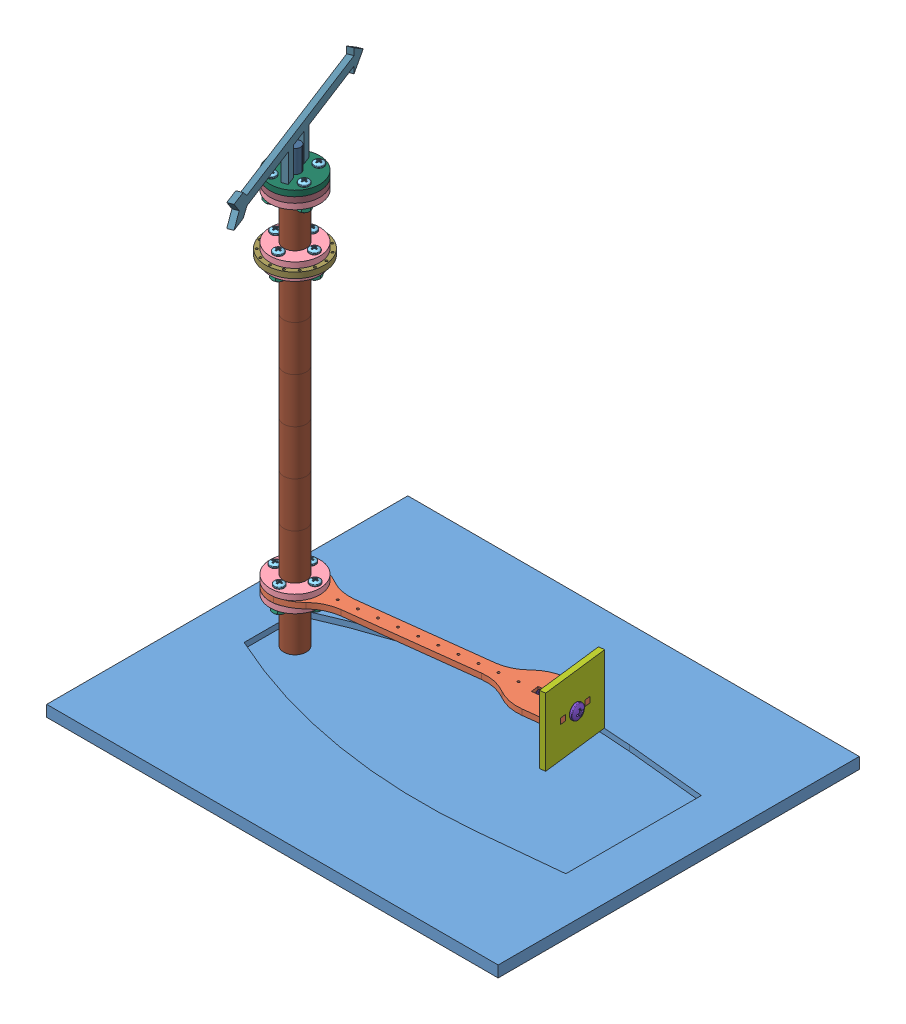
SolidWorks assembly boat_Assem1, configuration Default. Lengths in mm.
Overall size (254 259.72 203.2).
51 component instances, 15 part files, 81 mates.
Components (placement in the parent):
- base-1: base [Default] at (17.7481 -11.9296 -1.2606) size (254 6.35 203.2)
- boom_assembly-1: boom_assembly [Default] at (-15.1663 24.5072 -8.1814) x (0.992691 0 -0.12068) z (0.12068 0 0.992691) size (156.63 14.77 30.54)
  - boom-1: boom [Default] at (5.8183 -4.6868 0.1139) size (155.58 3.17 27.94)
  - bearing_57155K356-1: bearing_57155K356 [57155K356] at (-56.4117 -3.0993 0.1139) x (1 0 0) z (0 1 0) size (12.7 12.7 3.17)
  - boom_bearing_cap_hex-1: boom_bearing_cap_hex [Default] at (-56.4117 1.6632 0.1139) x (-1 0 0) z (0 0 1) size (27.94 3.17 27.94)
  - boom_bearing_cap_hex-3: boom_bearing_cap_hex [Default] at (-56.4117 -4.6868 0.1139) x (-1 0 0) z (0 0 1) size (27.94 3.17 27.94)
  - 440_1-2_90272A110-1: 440_1-2_90272A110 [90272A110] at (-46.2517 -11.0368 0.1139) x (1 0 0) z (0 1 0) size (5.56 5.56 14.77)
  - 440_1-2_90272A110-2: 440_1-2_90272A110 [90272A110] at (-56.4117 -11.0368 10.2739) x (1 0 0) z (0 1 0) size (5.56 5.56 14.77)
  - 440_1-2_90272A110-3: 440_1-2_90272A110 [90272A110] at (-66.5717 -11.0368 0.1139) x (1 0 0) z (0 1 0) size (5.56 5.56 14.77)
  - 440_1-2_90272A110-4: 440_1-2_90272A110 [90272A110] at (-56.4117 -11.0368 -10.0461) x (1 0 0) z (0 1 0) size (5.56 5.56 14.77)
  - 440_nut_90480A005-9: 440_nut_90480A005 [90480A005] at (-66.5717 -7.8618 0.1139) x (-0.837169 0 -0.546944) z (-0.546944 0 0.837169) size (6.35 2.38 8.06)
  - 440_nut_90480A005-10: 440_nut_90480A005 [90480A005] at (-56.4117 -7.8618 -10.0461) x (-0.837169 0 -0.546944) z (-0.546944 0 0.837169) size (6.35 2.38 8.06)
  - 440_nut_90480A005-11: 440_nut_90480A005 [90480A005] at (-46.2517 -7.8618 0.1139) x (-0.837169 0 -0.546944) z (-0.546944 0 0.837169) size (6.35 2.38 8.06)
  - 440_nut_90480A005-12: 440_nut_90480A005 [90480A005] at (-56.4117 -7.8618 10.2739) x (-0.837169 0 -0.546944) z (-0.546944 0 0.837169) size (6.35 2.38 8.06)
- calibration_part-1: calibration_part [Default] at (69.4182 21.4079 -18.3496) x (0.12068 0 0.992691) z (-0.992691 0 0.12068) size (38.1 38.1 3.17)
- 832screw_75-1: 832screw_75 [90272A197] at (50.5074 21.4079 -16.0506) x (0.015603 0.991607 0.128345) z (0.992691 0 -0.12068) size (8.18 8.18 22.03)
- 832squareNut-1: 832squareNut [94855A119] at (58.0717 21.4079 -16.9702) x (0 -1 0) z (0.12068 0 0.992691) size (8.73 3.17 8.73)
- mast-1: mast [Default] at (-71.1519 -11.9296 -1.2606) x (-0.874096 0 0.485753) z (-0.485753 0 -0.874096) size (6.35 247.65 6.35)
- spacer_93717A436-1: spacer_93717A436 [93717A436] at (-71.1519 3.9454 -1.2606) x (1 0 0) z (0 -1 0) size (12.7 12.7 25.4)
- sail_top-1: sail_top [Default] at (-71.1519 181.7454 -1.2606) x (-0.997292 0 0.073545) z (-0.073545 0 -0.997292) size (33.02 3.17 33.02)
- boom_bearing_cap_hex-1: boom_bearing_cap_hex [Default] at (-71.1519 178.5704 -1.2606) x (-0.997292 0 0.073545) z (-0.073545 0 -0.997292) size (27.94 3.17 27.94)
- boom_bearing_cap_hex-2: boom_bearing_cap_hex [Default] at (-71.1519 188.0954 -1.2606) x (-0.997292 0 0.073545) z (0.073545 0 0.997292) size (27.94 3.17 27.94)
- bearing_57155K356-1: bearing_57155K356 [57155K356] at (-71.1519 183.3329 -1.2606) x (1 0 0) z (0 -1 0) size (12.7 12.7 3.17)
- 440_1-2_90272A110-1: 440_1-2_90272A110 [90272A110] at (-71.8991 175.3954 -11.3931) x (1 0 0) z (0 1 0) size (5.56 5.56 14.77)
- 440_1-2_90272A110-2: 440_1-2_90272A110 [90272A110] at (-81.2844 175.3954 -0.5134) x (1 0 0) z (0 1 0) size (5.56 5.56 14.77)
- 440_1-2_90272A110-3: 440_1-2_90272A110 [90272A110] at (-61.0194 175.3954 -2.0078) x (1 0 0) z (0 1 0) size (5.56 5.56 14.77)
- 440_1-2_90272A110-4: 440_1-2_90272A110 [90272A110] at (-70.4047 175.3954 8.8719) x (1 0 0) z (0 1 0) size (5.56 5.56 14.77)
- 440_nut_90480A005-1: 440_nut_90480A005 [90480A005] at (-81.2844 178.5704 -0.5134) x (-0.837169 0 -0.546944) z (-0.546944 0 0.837169) size (6.35 2.38 8.06)
- 440_nut_90480A005-2: 440_nut_90480A005 [90480A005] at (-70.4047 178.5704 8.8719) x (-0.837169 0 -0.546944) z (-0.546944 0 0.837169) size (6.35 2.38 8.06)
- 440_nut_90480A005-3: 440_nut_90480A005 [90480A005] at (-61.0194 178.5704 -2.0078) x (-0.837169 0 -0.546944) z (-0.546944 0 0.837169) size (6.35 2.38 8.06)
- 440_nut_90480A005-4: 440_nut_90480A005 [90480A005] at (-71.8991 178.5704 -11.3931) x (-0.837169 0 -0.546944) z (-0.546944 0 0.837169) size (6.35 2.38 8.06)
- spacer_93717A436-2: spacer_93717A436 [93717A436] at (-71.1519 64.2704 -1.2606) x (1 0 0) z (0 -1 0) size (12.7 12.7 25.4)
- spacer_93717A436-4: spacer_93717A436 [93717A436] at (-71.1519 89.6704 -1.2606) x (1 0 0) z (0 -1 0) size (12.7 12.7 25.4)
- spacer_93717A436-6: spacer_93717A436 [93717A436] at (-71.1519 38.8704 -1.2606) x (0.837169 0 0.546944) z (0 1 0) size (12.7 12.7 25.4)
- spacer_93717A436-7: spacer_93717A436 [93717A436] at (-71.1519 115.0704 -1.2606) x (1 0 0) z (0 -1 0) size (12.7 12.7 25.4)
- spacer_93717A436-8: spacer_93717A436 [93717A436] at (-71.1519 140.4704 -1.2606) x (1 0 0) z (0 -1 0) size (12.7 12.7 25.4)
- spacer_93717A436-9: spacer_93717A436 [93717A436] at (-71.1519 165.8704 -1.2606) x (1 0 0) z (0 -1 0) size (12.7 12.7 25.4)
- spacer_93717A436-10: spacer_93717A436 [93717A436] at (-71.1519 200.7954 -1.2606) x (1 0 0) z (0 -1 0) size (12.7 12.7 25.4)
- vane_attach-1: vane_attach [Default] at (-71.1519 219.8454 -1.2606) x (0.914446 0 0.404708) z (0.404708 0 -0.914446) size (27.94 3.17 27.94)
- boom_bearing_cap_hex-4: boom_bearing_cap_hex [Default] at (-71.1519 213.4954 -1.2606) x (-0.404708 0 0.914446) z (-0.914446 0 -0.404708) size (27.94 3.17 27.94)
- bearing_57155K356-2: bearing_57155K356 [57155K356] at (-71.1519 218.2579 -1.2606) x (1 0 0) z (0 -1 0) size (12.7 12.7 3.17)
- wind_vane-1: wind_vane [Default] at (-69.6711 241.4354 -1.8328) x (0.360439 0 0.932783) z (-0.932783 0 0.360439) size (127 27.94 3.17)
- boom_bearing_cap-1: boom_bearing_cap [Default] at (-71.1519 223.0204 -1.2606) x (0.914446 0 0.404708) z (0.404708 0 -0.914446) size (27.94 3.17 27.94)
- 440_1-2_90272A110-5: 440_1-2_90272A110 [90272A110] at (-75.2638 210.3204 8.0301) x (1 0 0) z (0 1 0) size (5.56 5.56 14.77)
- 440_1-2_90272A110-6: 440_1-2_90272A110 [90272A110] at (-67.0401 210.3204 -10.5514) x (1 0 0) z (0 1 0) size (5.56 5.56 14.77)
- 440_1-2_90272A110-7: 440_1-2_90272A110 [90272A110] at (-80.4427 210.3204 -5.3725) x (1 0 0) z (0 1 0) size (5.56 5.56 14.77)
- 440_1-2_90272A110-8: 440_1-2_90272A110 [90272A110] at (-61.8611 210.3204 2.8512) x (1 0 0) z (0 1 0) size (5.56 5.56 14.77)
- 440_nut_90480A005-5: 440_nut_90480A005 [90480A005] at (-61.8611 213.4954 2.8512) x (-0.837169 0 -0.546944) z (-0.546944 0 0.837169) size (6.35 2.38 8.06)
- 440_nut_90480A005-6: 440_nut_90480A005 [90480A005] at (-67.0401 213.4954 -10.5514) x (-0.837169 0 -0.546944) z (-0.546944 0 0.837169) size (6.35 2.38 8.06)
- 440_nut_90480A005-7: 440_nut_90480A005 [90480A005] at (-75.2638 213.4954 8.0301) x (-0.837169 0 -0.546944) z (-0.546944 0 0.837169) size (6.35 2.38 8.06)
- 440_nut_90480A005-8: 440_nut_90480A005 [90480A005] at (-80.4427 213.4954 -5.3725) x (-0.837169 0 -0.546944) z (-0.546944 0 0.837169) size (6.35 2.38 8.06)
Mates (geometry in assembly coordinates):
- Coincident5: coincident anti-aligned: plane of boom_assembly-1/boom-1 through (64.5805 22.9954 -31.8343) normal (0.992691 0 -0.12068); plane of calibration_part-1 through (66.2664 21.4079 -17.9664) normal (-0.992691 0 0.12068)
- Coincident6: coincident anti-aligned: plane of boom_assembly-1/boom-1 through (70.1845 22.9954 -12.046) normal (-0.12068 0 -0.992691); plane of calibration_part-1 through (70.1845 22.9954 -12.046) normal (0.12068 0 0.992691)
- Coincident7: coincident anti-aligned: plane of boom_assembly-1/boom-1 through (-9.3767 22.9954 -8.7706) normal (0 1 0); plane of calibration_part-1 through (70.1845 22.9954 -12.046) normal (0 -1 0)
- Coincident8: coincident anti-aligned: plane of calibration_part-1 through (69.4182 21.4079 -18.3496) normal (0.992691 0 -0.12068); plane of 832screw_75-1 through (69.4182 21.4079 -18.3496) normal (-0.992691 0 0.12068)
- Concentric3: concentric anti-aligned: circle of calibration_part-1; circle of 832screw_75-1
- Coincident9: coincident anti-aligned: plane of boom_assembly-1/boom-1 through (60.6871 16.6454 -21.7659) normal (-0.992691 0 0.12068); plane of 832squareNut-1 through (60.6966 17.0423 -21.6871) normal (0.992691 0 -0.12068)
- Concentric4: concentric aligned: circle of 832screw_75-1; circle of 832squareNut-1
- Parallel2: parallel aligned: plane of boom_assembly-1/boom-1 through (-83.3339 22.9954 14.2932) normal (0.12068 0 0.992691); plane of 832squareNut-1 through (61.7503 25.7735 -13.0196) normal (0.12068 0 0.992691)
- Coincident11: coincident aligned: plane of base-1 through (17.7481 -11.9296 -1.2606) normal (0 -1 0); plane of mast-1 through (-71.1519 -11.9296 -1.2606) normal (0 -1 0)
- Coincident12: coincident aligned: circle of base-1; circle of mast-1
- Concentric5: concentric anti-aligned: circle of boom_assembly-1/boom_bearing_cap_hex-1; circle of mast-1
- Coincident14: coincident anti-aligned: plane of base-1 through (17.7481 -8.7546 -1.2606) normal (0 1 0); plane of spacer_93717A436-1 through (-71.1519 -8.7546 -1.2606) normal (0 -1 0)
- Concentric6: concentric aligned: circle of base-1; circle of spacer_93717A436-1
- Coincident15: coincident anti-aligned: plane of boom_assembly-1/boom_bearing_cap_hex-3 through (-71.1519 16.6454 -1.2606) normal (0 -1 0); plane of spacer_93717A436-1 through (-71.1519 16.6454 -1.2606) normal (0 1 0)
- Concentric7: concentric aligned: circle of mast-1; circle of sail_top-1
- Concentric8: concentric anti-aligned: circle of sail_top-1; circle of bearing_57155K356-1
- Coincident20: coincident aligned: plane of sail_top-1 through (-71.1519 184.9204 -1.2606) normal (0 1 0); plane of bearing_57155K356-1 through (-71.1519 184.9204 4.9306) normal (0 1 0)
- Concentric9: concentric aligned: circle of boom_bearing_cap_hex-2; circle of bearing_57155K356-1
- Coincident21: coincident anti-aligned: plane of sail_top-1 through (-71.1519 184.9204 -1.2606) normal (0 1 0); plane of boom_bearing_cap_hex-2 through (-71.1519 184.9204 -1.2606) normal (0 -1 0)
- Concentric10: concentric anti-aligned: circle of sail_top-1; circle of boom_bearing_cap_hex-2
- Coincident23: coincident anti-aligned: plane of sail_top-1 through (-71.1519 181.7454 -1.2606) normal (0 -1 0); plane of boom_bearing_cap_hex-1 through (-71.1519 181.7454 -1.2606) normal (0 1 0)
- Concentric11: concentric aligned: circle of sail_top-1; circle of boom_bearing_cap_hex-1
- Concentric12: concentric aligned: circle of sail_top-1; circle of boom_bearing_cap_hex-1
- Coincident25: coincident aligned: circle of boom_bearing_cap_hex-2; plane of 440_1-2_90272A110-4 through (-70.4047 188.0954 8.8719) normal (0 -1 0)
- Coincident26: coincident anti-aligned: plane of boom_bearing_cap_hex-2 through (-71.1519 188.0954 -1.2606) normal (0 1 0); plane of 440_1-2_90272A110-3 through (-61.0194 188.0954 -2.0078) normal (0 -1 0)
- Coincident27: coincident anti-aligned: plane of boom_bearing_cap_hex-2 through (-71.1519 188.0954 -1.2606) normal (0 1 0); plane of 440_1-2_90272A110-2 through (-81.2844 188.0954 -0.5134) normal (0 -1 0)
- Coincident28: coincident anti-aligned: plane of boom_bearing_cap_hex-2 through (-71.1519 188.0954 -1.2606) normal (0 1 0); plane of 440_1-2_90272A110-1 through (-71.8991 188.0954 -11.3931) normal (0 -1 0)
- Concentric13: concentric anti-aligned: circle of boom_bearing_cap_hex-2; circle of 440_1-2_90272A110-1
- Concentric14: concentric anti-aligned: circle of boom_bearing_cap_hex-2; circle of 440_1-2_90272A110-2
- Concentric15: concentric anti-aligned: circle of boom_bearing_cap_hex-2; circle of 440_1-2_90272A110-3
- Concentric16: concentric anti-aligned: circle of boom_bearing_cap_hex-2; circle of 440_1-2_90272A110-4
- Coincident30: coincident anti-aligned: plane of boom_bearing_cap_hex-1 through (-71.1519 178.5704 -1.2606) normal (0 -1 0); plane of 440_nut_90480A005-1 through (-79.2792 178.5704 -3.5826) normal (0 1 0)
- Coincident31: coincident anti-aligned: plane of boom_bearing_cap_hex-1 through (-71.1519 178.5704 -1.2606) normal (0 -1 0); plane of 440_nut_90480A005-2 through (-68.3995 178.5704 5.8027) normal (0 1 0)
- Coincident32: coincident anti-aligned: plane of boom_bearing_cap_hex-1 through (-71.1519 178.5704 -1.2606) normal (0 -1 0); plane of 440_nut_90480A005-4 through (-69.8939 178.5704 -14.4623) normal (0 1 0)
- Coincident33: coincident anti-aligned: plane of boom_bearing_cap_hex-1 through (-71.1519 178.5704 -1.2606) normal (0 -1 0); plane of 440_nut_90480A005-3 through (-59.0142 178.5704 -5.077) normal (0 1 0)
- Concentric17: concentric aligned: circle of boom_bearing_cap_hex-1; circle of 440_nut_90480A005-1
- Concentric18: concentric aligned: circle of boom_bearing_cap_hex-1; circle of 440_nut_90480A005-2
- Concentric19: concentric aligned: circle of boom_bearing_cap_hex-1; circle of 440_nut_90480A005-4
- Concentric20: concentric aligned: circle of boom_bearing_cap_hex-1; circle of 440_nut_90480A005-3
- Concentric21: concentric aligned: circle of mast-1; circle of spacer_93717A436-6
- Coincident34: coincident anti-aligned: plane of boom_assembly-1/boom_bearing_cap_hex-1 through (-71.1519 26.1704 -1.2606) normal (0 1 0); plane of spacer_93717A436-6 through (-71.1519 26.1704 -1.2606) normal (0 -1 0)
- Coincident35: coincident anti-aligned: plane of spacer_93717A436-2 through (-71.1519 51.5704 -1.2606) normal (0 -1 0); plane of spacer_93717A436-6 through (-71.1519 51.5704 -1.2606) normal (0 1 0)
- Concentric22: concentric anti-aligned: circle of spacer_93717A436-2; circle of spacer_93717A436-6
- Coincident39: coincident anti-aligned: plane of spacer_93717A436-2 through (-71.1519 76.9704 -1.2606) normal (0 1 0); plane of spacer_93717A436-4 through (-71.1519 76.9704 -1.2606) normal (0 -1 0)
- Concentric23: concentric aligned: circle of spacer_93717A436-2; circle of spacer_93717A436-4
- Coincident44: coincident anti-aligned: plane of spacer_93717A436-4 through (-71.1519 102.3704 -1.2606) normal (0 1 0); plane of spacer_93717A436-7 through (-71.1519 102.3704 -1.2606) normal (0 -1 0)
- Concentric25: concentric aligned: circle of spacer_93717A436-4; circle of spacer_93717A436-7
- Coincident46: coincident aligned: circle of spacer_93717A436-7; circle of spacer_93717A436-8
- Coincident47: coincident aligned: circle of spacer_93717A436-8; circle of spacer_93717A436-9
- Coincident48: coincident anti-aligned: plane of boom_bearing_cap_hex-1 through (-71.1519 178.5704 -1.2606) normal (0 -1 0); plane of spacer_93717A436-9 through (-71.1519 178.5704 -1.2606) normal (0 1 0)
- Coincident49: coincident anti-aligned: plane of boom_bearing_cap_hex-2 through (-71.1519 188.0954 -1.2606) normal (0 1 0); circle of spacer_93717A436-10
- Concentric26: concentric anti-aligned: circle of mast-1; circle of spacer_93717A436-10
- Concentric28: concentric aligned: circle of mast-1; circle of boom_bearing_cap_hex-4
- Coincident51: coincident anti-aligned: plane of spacer_93717A436-10 through (-71.1519 213.4954 -1.2606) normal (0 1 0); plane of boom_bearing_cap_hex-4 through (-71.1519 213.4954 -1.2606) normal (0 -1 0)
- Concentric29: concentric anti-aligned: circle of mast-1; circle of vane_attach-1
- Coincident53: coincident anti-aligned: plane of vane_attach-1 through (-71.1519 216.6704 -1.2606) normal (0 -1 0); plane of boom_bearing_cap_hex-4 through (-71.1519 216.6704 -1.2606) normal (0 1 0)
- Coincident56: coincident anti-aligned: plane of boom_bearing_cap_hex-4 through (-71.1519 216.6704 -1.2606) normal (0 1 0); plane of bearing_57155K356-2 through (-71.1519 216.6704 4.9306) normal (0 -1 0)
- Concentric32: concentric aligned: circle of vane_attach-1; circle of bearing_57155K356-2
- Concentric35: concentric anti-aligned: circle of vane_attach-1; circle of boom_bearing_cap_hex-4
- Concentric36: concentric anti-aligned: circle of mast-1; circle of boom_bearing_cap-1
- Coincident63: coincident anti-aligned: plane of vane_attach-1 through (-71.1519 219.8454 -1.2606) normal (0 1 0); plane of boom_bearing_cap-1 through (-71.1519 219.8454 -1.2606) normal (0 -1 0)
- Concentric37: concentric aligned: circle of vane_attach-1; circle of boom_bearing_cap-1
- Coincident66: coincident anti-aligned: plane of wind_vane-1 through (-73.3332 219.8454 -11.3099) normal (-0.360439 0 -0.932783); plane of boom_bearing_cap-1 through (-76.2948 224.9254 -10.1655) normal (0.360439 0 0.932783)
- Coincident67: coincident anti-aligned: plane of vane_attach-1 through (-71.1519 219.8454 -1.2606) normal (0 1 0); plane of wind_vane-1 through (-69.6711 219.8454 -1.8328) normal (0 -1 0)
- Coincident68: coincident anti-aligned: plane of wind_vane-1 through (-69.6711 241.4354 -1.8328) normal (0.932783 0 -0.360439); plane of boom_bearing_cap-1 through (-71.5022 224.9254 -6.5714) normal (-0.932783 0 0.360439)
- Concentric38: concentric anti-aligned: circle of boom_bearing_cap-1; circle of 440_1-2_90272A110-5
- Coincident69: coincident anti-aligned: plane of boom_bearing_cap-1 through (-71.1519 223.0204 -1.2606) normal (0 1 0); plane of 440_1-2_90272A110-5 through (-75.2638 223.0204 8.0301) normal (0 -1 0)
- Coincident70: coincident anti-aligned: plane of boom_bearing_cap-1 through (-71.1519 223.0204 -1.2606) normal (0 1 0); plane of 440_1-2_90272A110-7 through (-80.4427 223.0204 -5.3725) normal (0 -1 0)
- Coincident71: coincident anti-aligned: plane of boom_bearing_cap-1 through (-71.1519 223.0204 -1.2606) normal (0 1 0); plane of 440_1-2_90272A110-8 through (-61.8611 223.0204 2.8512) normal (0 -1 0)
- Coincident72: coincident anti-aligned: plane of boom_bearing_cap-1 through (-71.1519 223.0204 -1.2606) normal (0 1 0); plane of 440_1-2_90272A110-6 through (-67.0401 223.0204 -10.5514) normal (0 -1 0)
- Concentric39: concentric anti-aligned: circle of boom_bearing_cap-1; circle of 440_1-2_90272A110-7
- Concentric40: concentric anti-aligned: circle of boom_bearing_cap-1; circle of 440_1-2_90272A110-6
- Concentric41: concentric anti-aligned: circle of boom_bearing_cap-1; circle of 440_1-2_90272A110-8
- Coincident73: coincident anti-aligned: plane of boom_bearing_cap_hex-4 through (-71.1519 213.4954 -1.2606) normal (0 -1 0); plane of 440_nut_90480A005-5 through (-59.856 213.4954 -0.218) normal (0 1 0)
- Coincident74: coincident anti-aligned: plane of boom_bearing_cap_hex-4 through (-71.1519 213.4954 -1.2606) normal (0 -1 0); plane of 440_nut_90480A005-6 through (-65.0349 213.4954 -13.6206) normal (0 1 0)
- Coincident75: coincident anti-aligned: plane of boom_bearing_cap_hex-4 through (-71.1519 213.4954 -1.2606) normal (0 -1 0); plane of 440_nut_90480A005-8 through (-78.4375 213.4954 -8.4417) normal (0 1 0)
- Coincident76: coincident anti-aligned: plane of boom_bearing_cap_hex-4 through (-71.1519 213.4954 -1.2606) normal (0 -1 0); plane of 440_nut_90480A005-7 through (-73.2586 213.4954 4.9609) normal (0 1 0)
- Concentric42: concentric aligned: circle of boom_bearing_cap_hex-4; circle of 440_nut_90480A005-5
- Concentric43: concentric aligned: circle of boom_bearing_cap_hex-4; circle of 440_nut_90480A005-7
- Concentric44: concentric aligned: circle of boom_bearing_cap_hex-4; circle of 440_nut_90480A005-6
- Concentric45: concentric aligned: circle of boom_bearing_cap_hex-4; circle of 440_nut_90480A005-8
